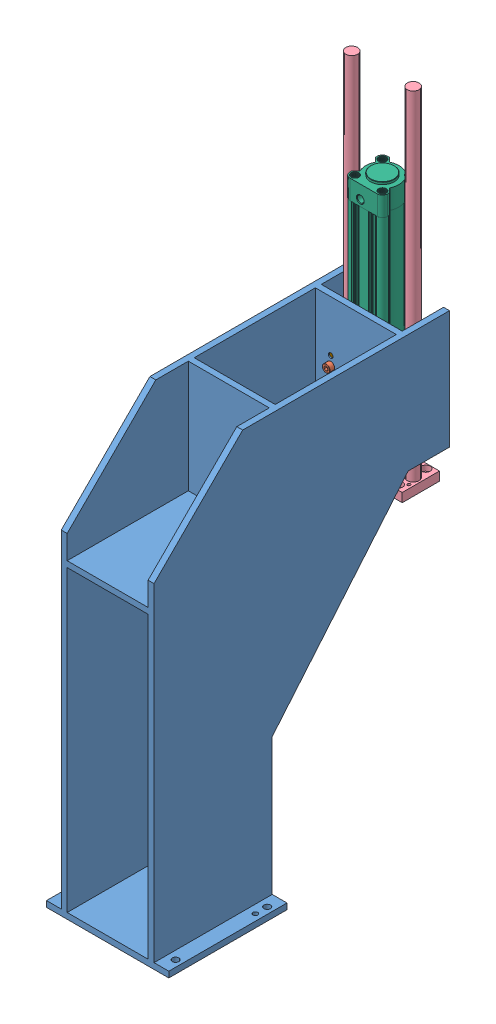
SolidWorks assembly Montagem prensa_desenho, configuration Default. Lengths in mm.
Overall size (207 1048.51 500).
20 component instances, 9 part files, 21 mates.
Components (placement in the parent):
- Suporte prensa-1: Suporte prensa [Default] at (129.4691 60.9907 640.0637) size (207 715.5 500)
- socket head cap screw_iso-2: socket head cap screw_iso [ISO 4762 M8 x 25 - 25N] at (18.4691 675.1907 228.0637) x (0 0 -1) z (1 0 0) size (33 13 13)
- socket head cap screw_iso-3: socket head cap screw_iso [ISO 4762 M8 x 25 - 25N] at (103.4691 675.1907 228.0637) x (0 0 -1) z (1 0 0) size (33 13 13)
- socket head cap screw_iso-4: socket head cap screw_iso [ISO 4762 M8 x 25 - 25N] at (103.4691 628.6907 228.0637) x (0 0 -1) z (0.172554 -0.985 0) size (33 13 13)
- socket head cap screw_iso-5: socket head cap screw_iso [ISO 4762 M8 x 25 - 25N] at (18.4691 628.6907 228.0637) x (0 0 -1) z (1 0 0) size (33 13 13)
- 150292 FENG-50-400-KF---(asm_0)-1: 150292 FENG-50-400-KF---(asm_0) [Default] at (60.9691 647.4907 175.0637) x (1 0 0) z (0 -1 0) size (137 70 588) (flexible)
  - 150292 FENG-50-KF---(GK)-1: 150292 FENG-50-KF---(GK) [Default] at origin size (137 70 150)
  - 150292 FENG-50-400-KF---(JS)-1: 150292 FENG-50-400-KF---(JS) [Default] at (0 0 36.9898) size (130 63 588)
  - DIN-912 - M8x40(F)-1: DIN-912 - M8x40(F) [Default] at (23.25 23.25 26) x (1 0 0) z (0 -1 0) size (13 48.35 13)
  - DIN-912 - M8x40(F)-2: DIN-912 - M8x40(F) [Default] at (-23.25 23.25 26) x (1 0 0) z (0 -1 0) size (13 48.35 13)
  - DIN-912 - M8x40(F)-3: DIN-912 - M8x40(F) [Default] at (23.25 -23.25 26) x (1 0 0) z (0 -1 0) size (13 48.35 13)
  - DIN-912 - M8x40(F)-4: DIN-912 - M8x40(F) [Default] at (-23.25 -23.25 26) x (1 0 0) z (0 -1 0) size (13 48.35 13)
- 1376310 DSBC-50-200-PPSA-N3---(0)-1: 1376310 DSBC-50-200-PPSA-N3---(0) [Default] at (60.9691 647.4907 175.0637) x (1 0 0) z (0 -1 0) size (64 64 420.99) (flexible)
  - 1463770 DSBC-50-200-PPSA_(Z_0)-1: 1463770 DSBC-50-200-PPSA_(Z_0) [Default] at origin size (64 64 336.8)
  - 1463770 DSBC-50-200_(K)-1: 1463770 DSBC-50-200_(K) [Default] at (0 0 43.1898) size (50 50 340.8)
  - DIN-439-B - M16x1_5(F)-1: DIN-439-B - M16x1_5(F) [Default] at (0 0 92.9898) x (1 0 0) z (0 -1 0) size (24 8 27.71)
- socket head cap screw_iso-16: socket head cap screw_iso [ISO 4762 M8 x 25 - 25N] at (18.4691 651.6907 228.0637) x (0 0 -1) z (1 0 0) size (33 13 13)
- socket head cap screw_iso-17: socket head cap screw_iso [ISO 4762 M8 x 25 - 25N] at (103.4691 651.6907 228.0637) x (0 0 -1) z (1 0 0) size (33 13 13)
- parallel pin hardened_iso-17: parallel pin hardened_iso [ISO 8734 - 8 x 26 - A - St] at (18.4691 690.1907 192.5637) x (0 0 1) z (-1 0 0) size (26 8 8)
- parallel pin hardened_iso-18: parallel pin hardened_iso [ISO 8734 - 8 x 26 - A - St] at (103.4691 613.6907 192.5637) x (0 0 1) z (-0.905211 -0.424962 0) size (26 8 8)
Mates (geometry in assembly coordinates):
- Concentric7: concentric aligned: cylinder of Suporte prensa-1 through (18.4691 675.1907 140.0627) axis (0 0 1) radius 4.5; cylinder of socket head cap screw_iso-2 through (18.4691 675.1907 259.8137) axis (0 0 1) radius 6.5
- Coincident6: coincident anti-aligned: plane of Suporte prensa-1 through (129.4691 60.9907 220.0637) normal (0 0 1); plane of socket head cap screw_iso-2 through (18.4691 681.6907 220.0637) normal (0 0 -1)
- Concentric8: concentric aligned: cylinder of Suporte prensa-1 through (103.4691 675.1907 140.0627) axis (0 0 1) radius 4.5; cylinder of socket head cap screw_iso-3 through (103.4691 675.1907 259.8137) axis (0 0 1) radius 6.5
- Coincident7: coincident anti-aligned: plane of Suporte prensa-1 through (129.4691 60.9907 220.0637) normal (0 0 1); plane of socket head cap screw_iso-3 through (103.4691 681.6907 220.0637) normal (0 0 -1)
- Concentric9: concentric aligned: cylinder of Suporte prensa-1 through (103.4691 628.6907 140.0627) axis (0 0 1) radius 4.5; cylinder of socket head cap screw_iso-4 through (103.4691 628.6907 259.8137) axis (0 0 1) radius 6.5
- Coincident8: coincident anti-aligned: plane of Suporte prensa-1 through (129.4691 60.9907 220.0637) normal (0 0 1); plane of socket head cap screw_iso-4 through (109.8716 629.8123 220.0637) normal (0 0 -1)
- Concentric10: concentric aligned: cylinder of Suporte prensa-1 through (18.4691 628.6907 140.0627) axis (0 0 1) radius 4.5; cylinder of socket head cap screw_iso-5 through (18.4691 628.6907 259.8137) axis (0 0 1) radius 6.5
- Coincident9: coincident anti-aligned: plane of Suporte prensa-1 through (129.4691 60.9907 220.0637) normal (0 0 1); plane of socket head cap screw_iso-5 through (18.4691 635.1907 220.0637) normal (0 0 -1)
- Coincident14: coincident anti-aligned: plane of Suporte prensa-1 through (129.4691 60.9907 210.0637) normal (0 0 -1); plane of 150292 FENG-50-400-KF---(asm_0)-1/150292 FENG-50-KF---(GK)-1 through (94.9691 647.4907 210.0637) normal (0 0 1)
- Concentric18: concentric aligned: cylinder of Suporte prensa-1 through (103.4691 613.6907 140.0627) axis (0 0 1) radius 4; cylinder of 150292 FENG-50-400-KF---(asm_0)-1/150292 FENG-50-KF---(GK)-1 through (103.4691 613.6907 192.5637) axis (0 0 1) radius 4
- Coincident23: coincident anti-aligned: plane of 150292 FENG-50-400-KF---(asm_0)-1/150292 FENG-50-KF---(GK)-1 through (93.7191 647.4907 210.0637) normal (0 1 0); plane of 1376310 DSBC-50-200-PPSA-N3---(0)-1/1463770 DSBC-50-200-PPSA_(Z_0)-1 through (29.9691 647.4907 195.4571) normal (0 -1 0)
- Concentric27: concentric aligned: circle of 150292 FENG-50-400-KF---(asm_0)-1/150292 FENG-50-KF---(GK)-1; circle of 1376310 DSBC-50-200-PPSA-N3---(0)-1/1463770 DSBC-50-200-PPSA_(Z_0)-1
- Coincident25: coincident anti-aligned: plane of 150292 FENG-50-400-KF---(asm_0)-1/150292 FENG-50-400-KF---(JS)-1 through (60.9691 536.5009 175.0637) normal (0 1 0); plane of 1376310 DSBC-50-200-PPSA-N3---(0)-1/1463770 DSBC-50-200_(K)-1 through (60.9691 536.5009 175.0637) normal (0 -1 0)
- Concentric42: concentric aligned: cylinder of Suporte prensa-1 through (18.4691 651.6907 140.0627) axis (0 0 1) radius 4.5; cylinder of socket head cap screw_iso-16 through (18.4691 651.6907 259.8137) axis (0 0 1) radius 6.5
- Coincident35: coincident anti-aligned: plane of Suporte prensa-1 through (129.4691 60.9907 220.0637) normal (0 0 1); plane of socket head cap screw_iso-16 through (18.4691 658.1907 220.0637) normal (0 0 -1)
- Concentric43: concentric aligned: cylinder of Suporte prensa-1 through (103.4691 651.6907 140.0627) axis (0 0 1) radius 4.5; cylinder of socket head cap screw_iso-17 through (103.4691 651.6907 259.8137) axis (0 0 1) radius 6.5
- Coincident36: coincident anti-aligned: plane of Suporte prensa-1 through (129.4691 60.9907 220.0637) normal (0 0 1); plane of socket head cap screw_iso-17 through (103.4691 658.1907 220.0637) normal (0 0 -1)
- Concentric44: concentric aligned: cylinder of Suporte prensa-1 through (18.4691 690.1907 140.0627) axis (0 0 1) radius 4; cone of parallel pin hardened_iso-17 through (18.4691 690.1907 218.5637) axis (0 0 1)
- Concentric45: concentric aligned: cylinder of Suporte prensa-1 through (103.4691 613.6907 140.0627) axis (0 0 1) radius 4; cone of parallel pin hardened_iso-18 through (103.4691 613.6907 218.5637) axis (0 0 1)
- Coincident37: coincident anti-aligned: plane of 150292 FENG-50-400-KF---(asm_0)-1/150292 FENG-50-KF---(GK)-1 through (18.4691 690.1907 192.5637) normal (0 0 1); plane of parallel pin hardened_iso-17 through (18.4691 693.762 192.5637) normal (0 0 -1)
- Coincident38: coincident anti-aligned: plane of 150292 FENG-50-400-KF---(asm_0)-1/150292 FENG-50-KF---(GK)-1 through (103.4691 613.6907 192.5637) normal (0 0 1); plane of parallel pin hardened_iso-18 through (101.9515 616.9234 192.5637) normal (0 0 -1)
